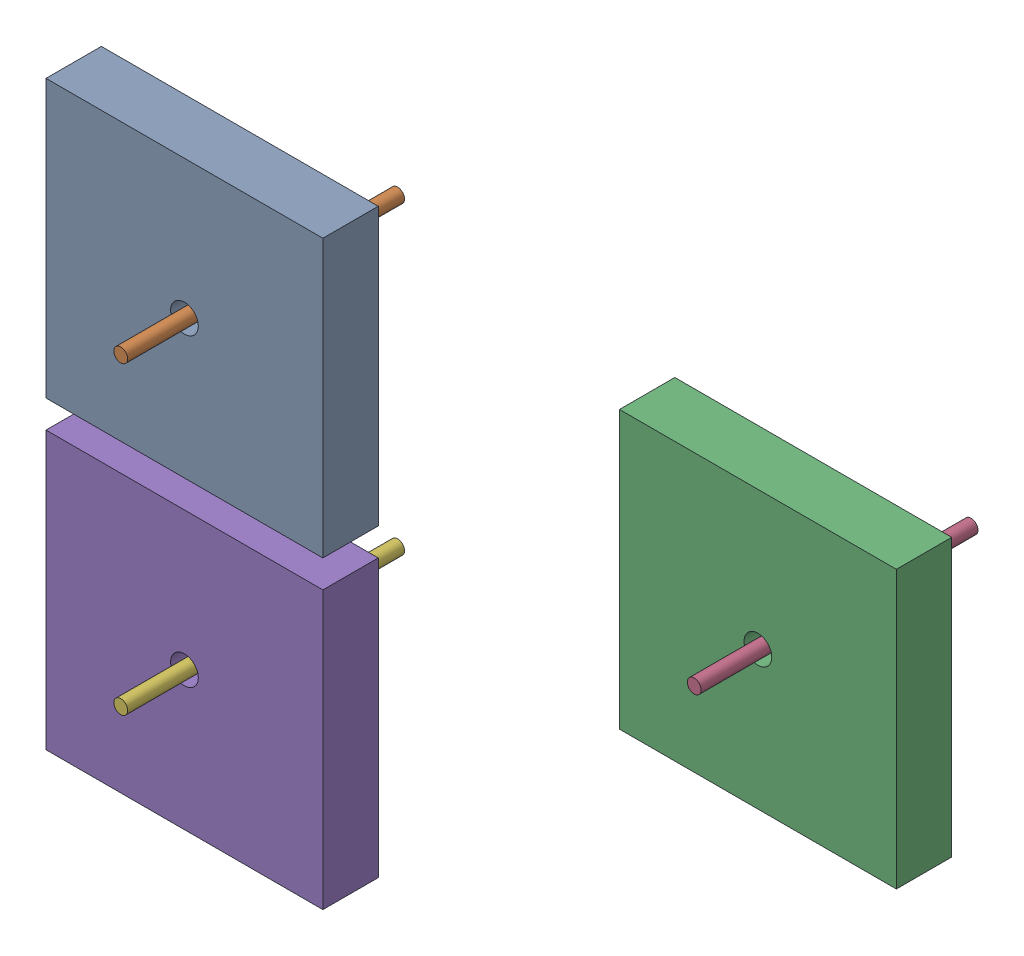
SolidWorks assembly Assem2, configuration ﾃﾞﾌｫﾙﾄ. Lengths in mm.
Overall size (30.71 21 10).
9 component instances, 2 part files, 2 mates.
Components (placement in the parent):
- Assem1-1: Assem1 [ﾃﾞﾌｫﾙﾄ] at (-3.3919 2.5696 0) size (10 10 10)
  - base-1: base [ﾃﾞﾌｫﾙﾄ] at (3.0632 -2.1704 0) size (10 10 2)
  - cylinder-1: cylinder [ﾃﾞﾌｫﾙﾄ] at (3.0632 -2.1704 -5.6987) size (0.5 0.5 10)
- Assem1-2: Assem1 [ﾃﾞﾌｫﾙﾄ] at (17.3188 2.5696 0) size (10 10 10)
  - base-1: base [ﾃﾞﾌｫﾙﾄ] at (3.0632 -2.1704 0) size (10 10 2)
  - cylinder-1: cylinder [ﾃﾞﾌｫﾙﾄ] at (3.0632 -2.1704 -5.6987) size (0.5 0.5 10)
- Assem1-3: Assem1 [ﾃﾞﾌｫﾙﾄ] at (-3.3919 -8.4304 0) size (10 10 10)
  - base-1: base [ﾃﾞﾌｫﾙﾄ] at (3.0632 -2.1704 0) size (10 10 2)
  - cylinder-1: cylinder [ﾃﾞﾌｫﾙﾄ] at (3.0632 -2.1704 -5.6987) size (0.5 0.5 10)
Mates (geometry in assembly coordinates):
- 平行3: parallel aligned: plane of Assem1-1/base-1 through (-5.3288 -4.6008 2) normal (0 -1 0); plane of Assem1-2/base-1 through (15.382 -4.6008 2) normal (0 -1 0)
- 平行4: parallel aligned: plane of Assem1-1/base-1 through (-0.3288 0.3992 2) normal (0 0 1); plane of Assem1-2/base-1 through (20.382 0.3992 2) normal (0 0 1)
